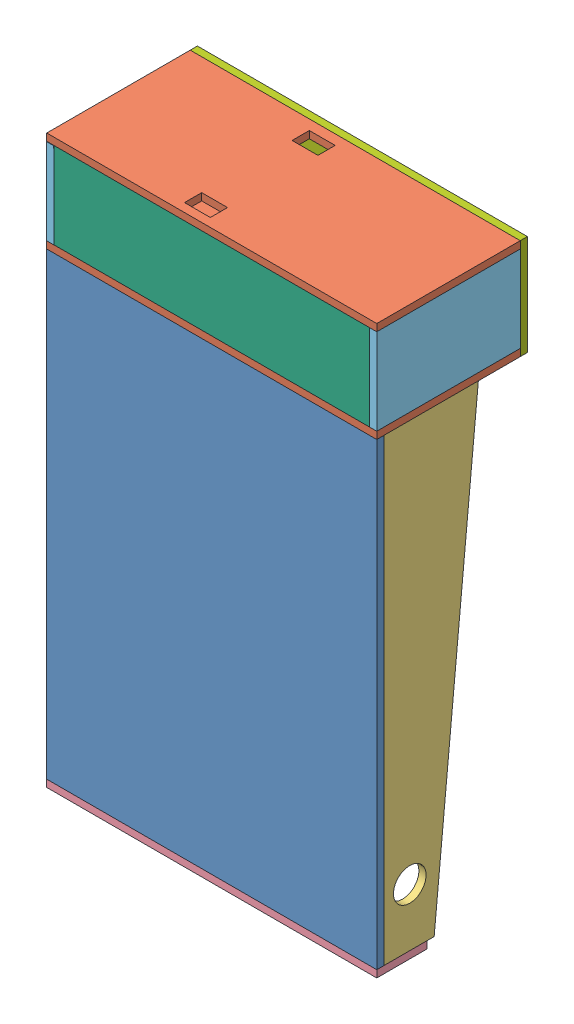
SolidWorks assembly pinball enclosure, configuration Default. Lengths in mm.
Overall size (292.1 501.65 133.49).
10 component instances, 7 part files, 20 mates.
Components (placement in the parent):
- base-1: base [Default] at (-22.2042 13.1183 317.2401) size (292.1 406.4 6.35)
- backboard-1: backboard [Default] at (-22.2042 425.8683 196.5901) x (1 0 0) z (0 -1 0) size (292.1 127 6.35)
- side panel-1: side panel [Default] at (263.5458 419.5183 317.2401) x (0 -1 0) z (1 0 0) size (406.4 83.57 6.35)
- side panel-2: side panel [Default] at (-22.2042 419.5183 317.2401) x (0 -1 0) z (1 0 0) size (406.4 83.57 6.35)
- front panel-1: front panel [Default] at (-22.2042 6.7683 323.5901) x (1 0 0) z (0 1 0) size (292.1 57.15 6.35)
- backboard side panel-1: backboard side panel [Default] at (263.5458 502.0683 323.5901) x (0 -1 0) z (1 0 0) size (76.2 127 6.35)
- backboard base-1: backboard base [Default] at (-15.8542 425.8683 317.2401) size (279.4 76.2 6.35)
- backboard-2: backboard [Default] at (-22.2042 508.4183 196.5901) x (1 0 0) z (0 -1 0) size (292.1 127 6.35)
- backboard top-1: backboard top [Default] at (-22.2042 419.5183 190.2401) size (292.1 88.9 6.35)
- backboard side panel-3: backboard side panel [Default] at (-15.8542 425.6263 323.5898) x (0 0.999998 0.001905) z (-1 0 0) size (76.2 127 6.35)
Mates (geometry in assembly coordinates):
- Coincident1: coincident anti-aligned: line of base-1 through (269.8958 419.5183 323.5901) axis (-1 0 0); line of backboard-1 through (-22.2042 419.5183 323.5901) axis (1 0 0)
- Coincident2: coincident anti-aligned: plane of base-1 through (-22.2042 419.5183 323.5901) normal (0 1 0); plane of backboard-1 through (-22.2042 419.5183 196.5901) normal (0 -1 0)
- Coincident3: coincident anti-aligned: line of base-1 through (-22.2042 419.5183 323.5901) axis (0 0 -1); line of backboard-1 through (-22.2042 419.5183 196.5901) axis (0 0 1)
- Coincident17: coincident: point of base-1; point of side panel-1
- Coincident18: coincident aligned: line of base-1 through (269.8958 13.1183 323.5901) axis (0 0 -1); line of side panel-1 through (269.8958 13.1183 317.2401) axis (0 0 -1)
- Coincident19: coincident: point of base-1; point of side panel-2
- Coincident20: coincident aligned: line of base-1 through (-22.2042 13.1183 323.5901) axis (0 0 -1); line of side panel-2 through (-22.2042 13.1183 317.2401) axis (0 0 -1)
- Coincident21: coincident: point of base-1; point of front panel-1
- Coincident22: coincident: point of base-1; point of front panel-1
- Coincident23: coincident: point of base-1; point of front panel-1
- Coincident24: coincident: point of base-1; point of front panel-1
- Coincident26: coincident anti-aligned: line of backboard-1 through (269.8958 425.8683 196.5901) axis (0 0 1); line of backboard side panel-1 through (269.8958 425.8683 323.5901) axis (0 0 -1)
- Coincident27: coincident: point of backboard-1; point of backboard side panel-1
- Coincident28: coincident anti-aligned: line of backboard-1 through (269.8958 419.5183 323.5901) axis (0 1 0); line of backboard side panel-1 through (269.8958 502.0683 323.5901) axis (0 -1 0)
- Parallel3: parallel anti-aligned: plane of backboard-1 through (-22.2042 425.8683 196.5901) normal (0 1 0); plane of backboard base-1 through (-15.8542 425.8683 323.5901) normal (0 -1 0)
- Coincident37: coincident: line of backboard side panel-1 through (263.5458 502.0683 196.5901) axis (0 0 1); point of backboard base-1
- Coincident38: coincident: point of backboard-1; point of backboard top-1
- Coincident39: coincident: point of backboard-2; point of backboard top-1
- Coincident44: coincident anti-aligned: line of backboard side panel-1 through (263.5458 502.0683 323.5901) axis (0 -1 0); line of backboard base-1 through (263.5458 425.8683 323.5901) axis (0 1 0)
- Coincident50: coincident: point of backboard-1; point of backboard side panel-3
